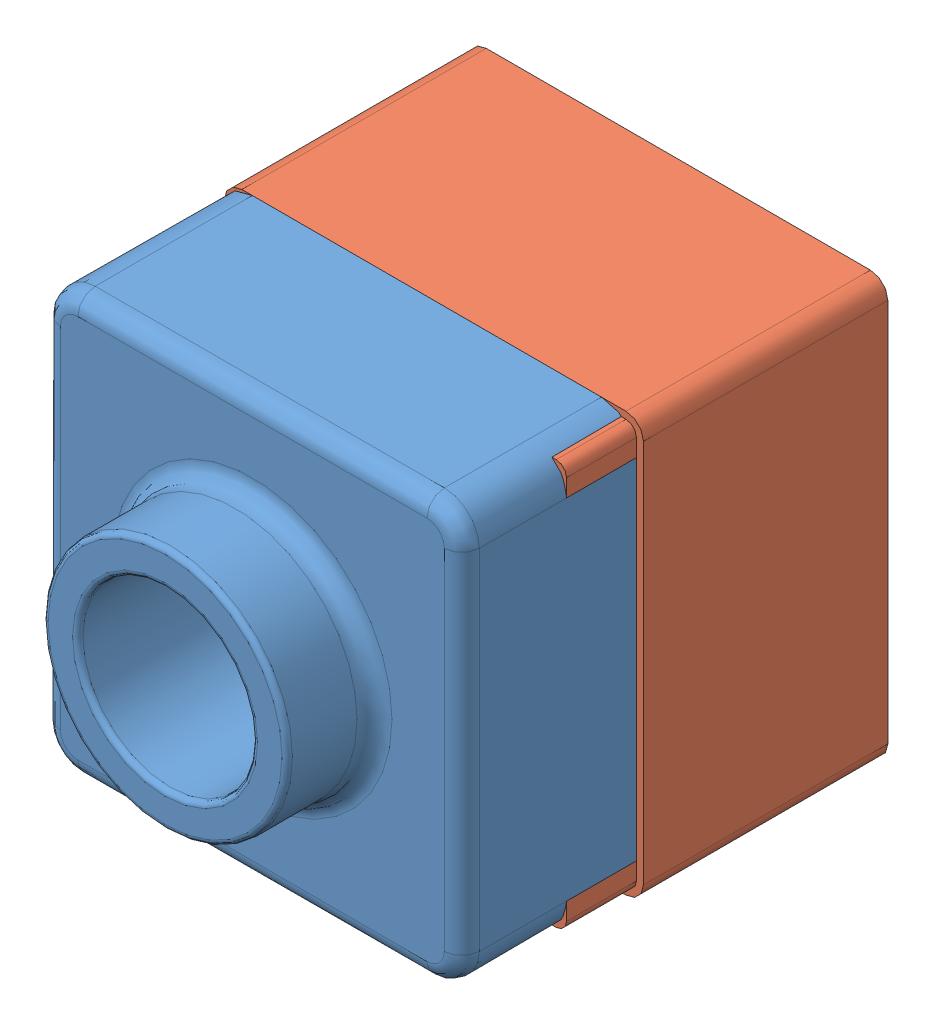
SolidWorks assembly Tutor, configuration Default. Lengths in mm.
Overall size (122 120 145).
2 component instances, 2 part files, 2 mates.
Components (placement in the parent):
- Tutor1-2: Tutor1 [Default] at (0.9079 103.8695 -71.0465) size (120 120 75)
- Tutor2-3: Tutor2 [Default] at (-37.442 57.3147 -141.0465) size (120 120 90)
Mates (geometry in assembly coordinates):
- Coincident1: coincident aligned: line of Tutor1-2 through (-28.3308 28.4721 -71.0465) axis (-1 0 0); line of Tutor2-3 through (-21.3308 28.4721 -71.0465) axis (-1 0 0)
- Coincident2: coincident aligned: line of Tutor2-3 through (-18.3308 -86.5279 -71.0465) axis (0 1 0); line of Tutor1-2 through (-18.3308 -81.5279 -71.0465) axis (0 1 0)
